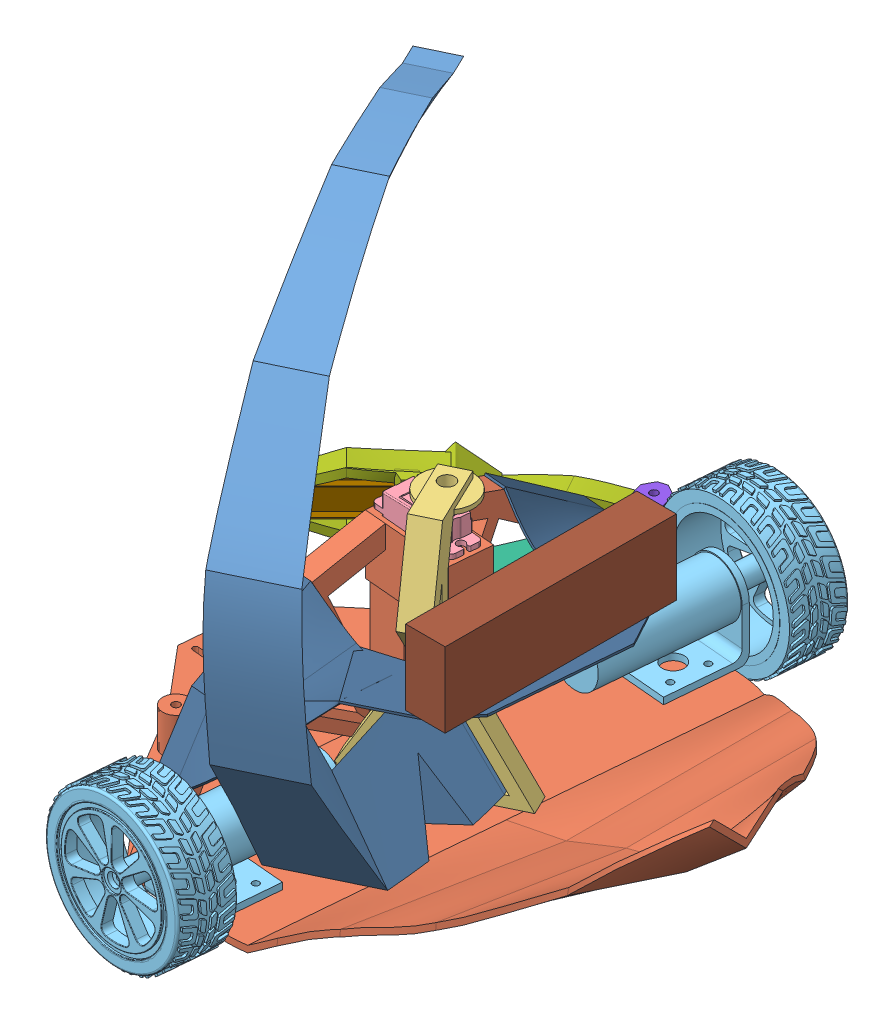
SolidWorks assembly Ass_cauda, configuration Default. Lengths in mm.
Overall size (301.08 358.68 332.93).
12 component instances, 11 part files, 28 mates.
Components (placement in the parent):
- cauda-1: cauda [Default] at (-141.1236 -88.6293 34.7144) x (0.433313 0 0.901244) z (-0.901244 0 0.433313) size (181.08 284.92 51.98)
- cauda_3-1: cauda_3 [Default] at (-159.0867 -139.1388 11.3702) x (0.996264 0 0.086356) z (-0.086356 0 0.996264) size (262.29 97.5 223.1)
- cauda_encaixe-1: cauda_encaixe [Default] at (-140.348 -118.1388 34.3415) x (-0.901244 0 0.433313) z (-0.433313 0 -0.901244) size (71.01 112.5 44.57)
- Servo S05NF-1: Servo S05NF [Default] at (-156.2624 -68.6388 19.8959) x (0.996264 0 0.086356) z (-0.086356 0 0.996264) size (39.75 35.2 13.5)
- Ass_Motor-1: Ass_Motor [Default] at (-239.6322 -133.7699 38.0281) x (-0.996264 0 -0.086356) z (-0.086356 0 0.996264) size (68.01 68.01 88)
- Ass_Motor-2: Ass_Motor [Default] at (-54.9299 -133.7699 1.8151) x (0.996264 0 0.086356) z (0.086356 0 -0.996264) size (68.01 68.01 88)
- patinha-1: patinha [Default] at (-211.7454 -144.1388 -41.2524) x (-0.527623 0 0.849479) z (-0.849479 0 -0.527623) size (76.7 24.06 19.92)
- garra-1: garra [Default] at (-242.7704 -122.0743 -65.1852) x (-0.705985 0 -0.708227) z (0.708227 0 -0.705985) size (30.79 29.53 129.25)
- união-1: união [Default] at (-180.4781 -119.5779 -118.8307) x (0.288364 0 0.957521) z (-0.957521 0 0.288364) size (28 14.5 12)
- Long Range SHARP IR Sensors - #GP2Y0A21YK0F-1: Long Range SHARP IR Sensors - #GP2Y0A21YK0F [Default] at (-241.3253 -128.3474 -50.6704) x (-0.708227 0 0.705985) z (-0.705985 0 -0.708227) size (44.5 18.9 13.5)
- topcoverback-1: topcoverback [Default] at (-173.7788 -86.617 99.8095) x (0.071759 0.556319 -0.827864) z (0.996264 0 0.086356) size (168.38 126.29 86.32)
- bateria-1: bateria [Default] at (-113.377 -39.843 -32.4659) x (-0.000092 -0.999999 0.001062) z (-0.001062 0.001062 0.999999) size (34 18 105)
Mates (geometry in assembly coordinates):
- Tangent1: tangent: face of cauda-1; plane of cauda_encaixe-1 through (-168.8767 -133.6388 36.9621) normal (0.7805 -0.5 -0.37526)
- Tangent2: tangent: face of cauda-1; plane of cauda_encaixe-1 through (-120.4857 -133.6388 13.696) normal (0 1 0)
- Coincident1: coincident anti-aligned: plane of cauda-1 through (-145.4567 -88.6293 25.7019) normal (-0.433313 0 -0.901244); plane of cauda_encaixe-1 through (-144.6812 -118.1388 25.3291) normal (0.433313 0 0.901244)
- Concentric1: concentric aligned: cylinder of cauda_3-1 through (-147.281 -49.6388 19.9216) axis (0 -1 0) radius 1.75; cylinder of cauda_encaixe-1 through (-147.281 -77.1388 19.9216) axis (0 -1 0) radius 1.75
- Coincident2: coincident anti-aligned: plane of cauda_3-1 through (-140.4567 -76.6388 28.0412) normal (0 -1 0); plane of cauda_encaixe-1 through (-147.281 -76.6388 19.9216) normal (0 1 0)
- Coincident3: coincident anti-aligned: plane of cauda_3-1 through (-168.3521 -68.6388 25.6233) normal (0 1 0); plane of Servo S05NF-1 through (-156.2624 -68.6388 19.8959) normal (0 -1 0)
- Coincident4: coincident aligned: plane of cauda_3-1 through (-160.382 -139.1388 26.3141) normal (-0.086356 0 0.996264); plane of Servo S05NF-1 through (-171.3409 -48.8388 25.3642) normal (-0.086356 0 0.996264)
- Coincident5: coincident anti-aligned: plane of cauda_3-1 through (-171.3409 -68.6388 25.3642) normal (0.996264 0 0.086356); plane of Servo S05NF-1 through (-171.3409 -48.8388 25.3642) normal (-0.996264 0 -0.086356)
- Coincident6: coincident anti-aligned: plane of cauda_3-1 through (-159.0867 -144.1388 11.3702) normal (0 1 0); plane of Ass_Motor-1 through (-141.2381 -144.1388 100.7454) normal (0 -1 0)
- Parallel1: parallel aligned: plane of cauda_3-1 through (-177.3185 -49.6388 24.8461) normal (-0.996264 0 -0.086356); plane of Ass_Motor-1 through (-167.1409 -141.1388 98.5001) normal (-0.996264 0 -0.086356)
- Coincident8: coincident aligned: plane of Ass_Motor-1 through (-167.1409 -141.1388 98.5001) normal (-0.996264 0 -0.086356); plane of Ass_Motor-2 through (-153.324 -141.1388 -60.9022) normal (-0.996264 0 -0.086356)
- Coincident9: coincident anti-aligned: plane of cauda_3-1 through (-159.0867 -144.1388 11.3702) normal (0 1 0); plane of Ass_Motor-2 through (-153.324 -144.1388 -60.9022) normal (0 -1 0)
- Distance1: distance = 16.5 mm aligned: plane of Ass_Motor-2 through (-153.324 -141.1388 -60.9022) normal (-0.996264 0 -0.086356); plane of cauda_3-1 through (-177.3185 -49.6388 24.8461) normal (-0.996264 0 -0.086356)
- Distance2: distance = 30 mm: plane of Ass_Motor-2 through (-153.324 -144.1388 -60.9022) normal (-0.086356 0 0.996264); line of cauda_3-1 through (-157.2091 -144.1388 -91.3514) axis (0.996264 0 0.086356)
- Distance3: distance = 30 mm: plane of Ass_Motor-1 through (-141.2381 -144.1388 100.7454) normal (0.086356 0 -0.996264); line of cauda_3-1 through (-139.7413 -144.1388 130.9876) axis (-0.996264 0 -0.086356)
- Concentric2: concentric aligned: cylinder of cauda_3-1 through (-211.7454 -127.1388 -41.2524) axis (0 -1 0) radius 6; cylinder of patinha-1 through (-211.7454 -127.1388 -41.2524) axis (0 -1 0) radius 6.35
- Coincident14: coincident anti-aligned: plane of cauda_3-1 through (-211.7454 -127.1388 -41.2524) normal (0 1 0); plane of patinha-1 through (-211.7454 -127.1388 -41.2524) normal (0 -1 0)
- Concentric3: concentric aligned: circle of garra-1; circle of união-1
- Coincident15: coincident anti-aligned: plane of garra-1 through (-183.4847 -119.5779 -116.8821) normal (0 1 0); plane of união-1 through (-191.9684 -119.5779 -115.3703) normal (0 -1 0)
- Coincident16: coincident anti-aligned: plane of patinha-1 through (-169.5754 -126.0779 -95.5211) normal (0 -1 0); plane of união-1 through (-183.8942 -126.0779 -88.5597) normal (0 1 0)
- Concentric4: concentric anti-aligned: circle of patinha-1; circle of união-1
- Coincident19: coincident anti-aligned: plane of garra-1 through (-239.2404 -122.0743 -61.6441) normal (-0.705985 0 -0.708227); plane of Long Range SHARP IR Sensors - #GP2Y0A21YK0F-1 through (-269.3216 -122.0743 -31.6582) normal (0.705985 0 0.708227)
- Concentric5: concentric aligned: circle of garra-1; circle of Long Range SHARP IR Sensors - #GP2Y0A21YK0F-1
- Parallel2: parallel anti-aligned: plane of cauda_3-1 through (-159.0867 -144.1388 11.3702) normal (0 1 0); plane of Long Range SHARP IR Sensors - #GP2Y0A21YK0F-1 through (-241.3253 -128.3474 -50.6704) normal (0 -1 0)
- Coincident22: coincident anti-aligned: plane of cauda_3-1 through (-173.762 -86.4865 99.6154) normal (-0.048041 0.830969 0.554241); plane of topcoverback-1 through (-180.1535 -58.801 57.5527) normal (0.048041 -0.830969 -0.554241)
- Coincident24: coincident anti-aligned: plane of topcoverback-1 through (-173.7776 -73.697 99.7958) normal (0.000092 0.999999 -0.001062); plane of bateria-1 through (-113.4916 -73.7315 72.5701) normal (-0.000092 -0.999999 0.001062)
- Coincident26: coincident aligned: plane of cauda_3-1 through (-177.3185 -49.6388 24.8461) normal (-0.996264 0 -0.086356); plane of topcoverback-1 through (-183.7414 -86.617 98.9459) normal (-0.996264 0 -0.086356)
- Coincident27: coincident anti-aligned: line of cauda_3-1 through (-170.1909 -58.801 58.4163) axis (-0.996264 0 -0.086356); line of topcoverback-1 through (-180.1535 -58.801 57.5527) axis (0.996264 0 0.086356)
